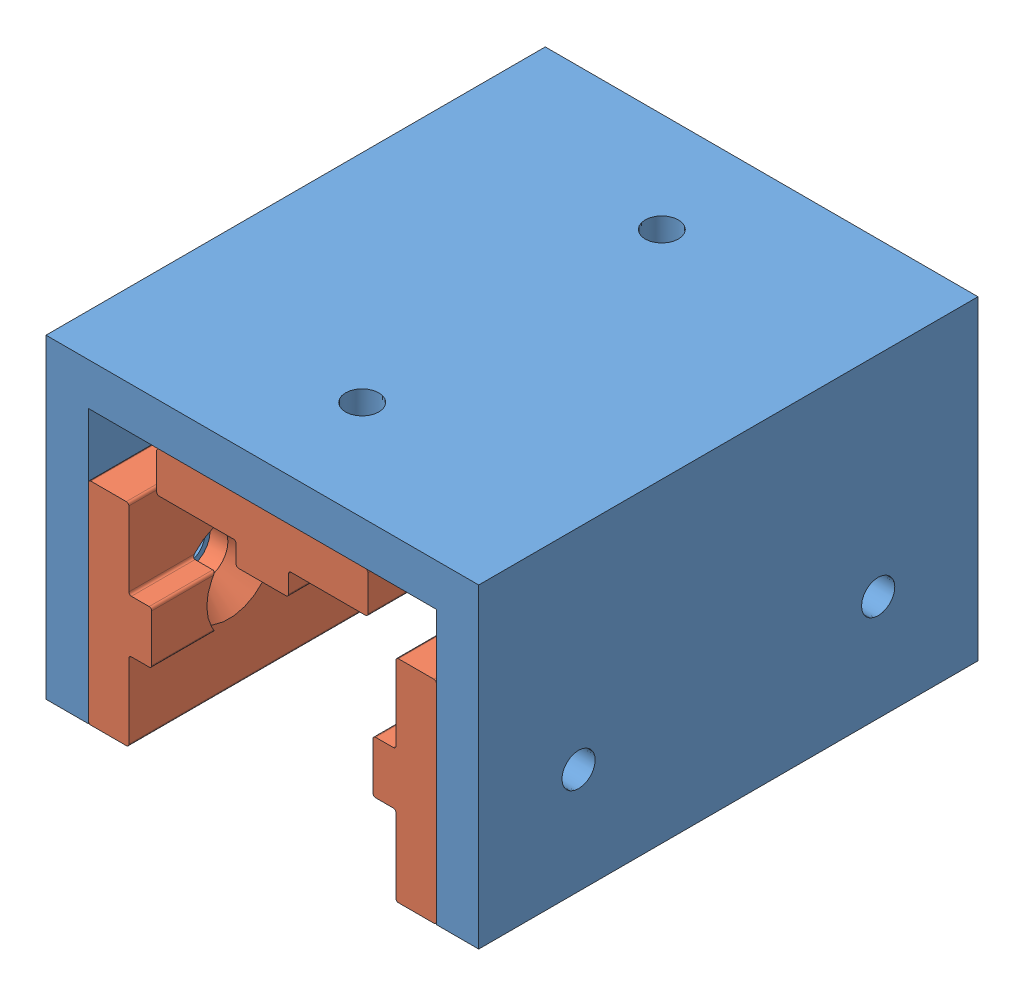
SolidWorks assembly Frame Carriage Assembly, configuration Default. Lengths in mm.
Overall size (65 47.37 75).
4 component instances, 2 part files, 9 mates.
Components (placement in the parent):
- Frame Carriage Body-1: Frame Carriage Body [Default] at (-13.8584 24.4943 17.1884) size (65 47.37 75)
- Frame Carriage Bearing-1: Frame Carriage Bearing [Default] at (-1.4124 40.3683 29.8884) size (9.53 31.75 75)
- Frame Carriage Bearing-2: Frame Carriage Bearing [Default] at (38.6956 40.3683 29.8884) x (-1 0 0) z (0 0 1) size (9.53 31.75 75)
- Frame Carriage Bearing-3: Frame Carriage Bearing [Default] at (18.6416 59.4183 79.4884) x (0 -1 0) z (0 0 -1) size (9.53 31.75 75)
Mates (geometry in assembly coordinates):
- Coincident1: coincident: plane of Frame Carriage Body-1 through (-13.8584 24.4943 92.1884) normal (0 0 1); plane of Frame Carriage Bearing-1 through (-7.1274 55.8623 92.1884) normal (0 0 1)
- Coincident2: coincident: plane of Frame Carriage Body-1 through (-13.8584 24.4943 92.1884) normal (0 0 1); plane of Frame Carriage Bearing-3 through (34.1356 65.1333 92.1884) normal (0 0 1)
- Coincident3: coincident: plane of Frame Carriage Body-1 through (-13.8584 24.4943 92.1884) normal (0 0 1); plane of Frame Carriage Bearing-2 through (44.4106 24.8743 92.1884) normal (0 0 1)
- Coincident4: coincident: plane of Frame Carriage Body-1 through (-7.5084 24.4943 92.1884) normal (1 0 0); plane of Frame Carriage Bearing-1 through (-7.5084 55.8623 42.5884) normal (-1 0 0)
- Coincident5: coincident: plane of Frame Carriage Body-1 through (44.7916 58.0143 92.1884) normal (-1 0 0); plane of Frame Carriage Bearing-2 through (44.7916 24.8743 42.5884) normal (1 0 0)
- Coincident6: coincident: plane of Frame Carriage Body-1 through (-0.0084 65.5143 92.1884) normal (0 -1 0); plane of Frame Carriage Bearing-3 through (3.1476 65.5143 66.7884) normal (0 1 0)
- Distance2: distance = 19.05 mm: moEndPointRef_w of Frame Carriage Bearing-1; line of Frame Carriage Bearing-3 through (14.3236 59.4183 92.1884) axis (-1 0 0)
- Coincident10: coincident: plane of Frame Carriage Bearing-1 through (-7.1274 24.4933 42.5884) normal (0 -1 0); plane of Frame Carriage Bearing-2 through (39.0766 24.4933 42.5884) normal (0 -1 0)
- Symmetric1: symmetric: plane of Frame Carriage Bearing-3 through (2.7666 59.7993 66.7884) normal (-1 0 0); plane of Frame Carriage Bearing-3 through (34.5166 65.1333 66.7884) normal (1 0 0); plane of assembly
